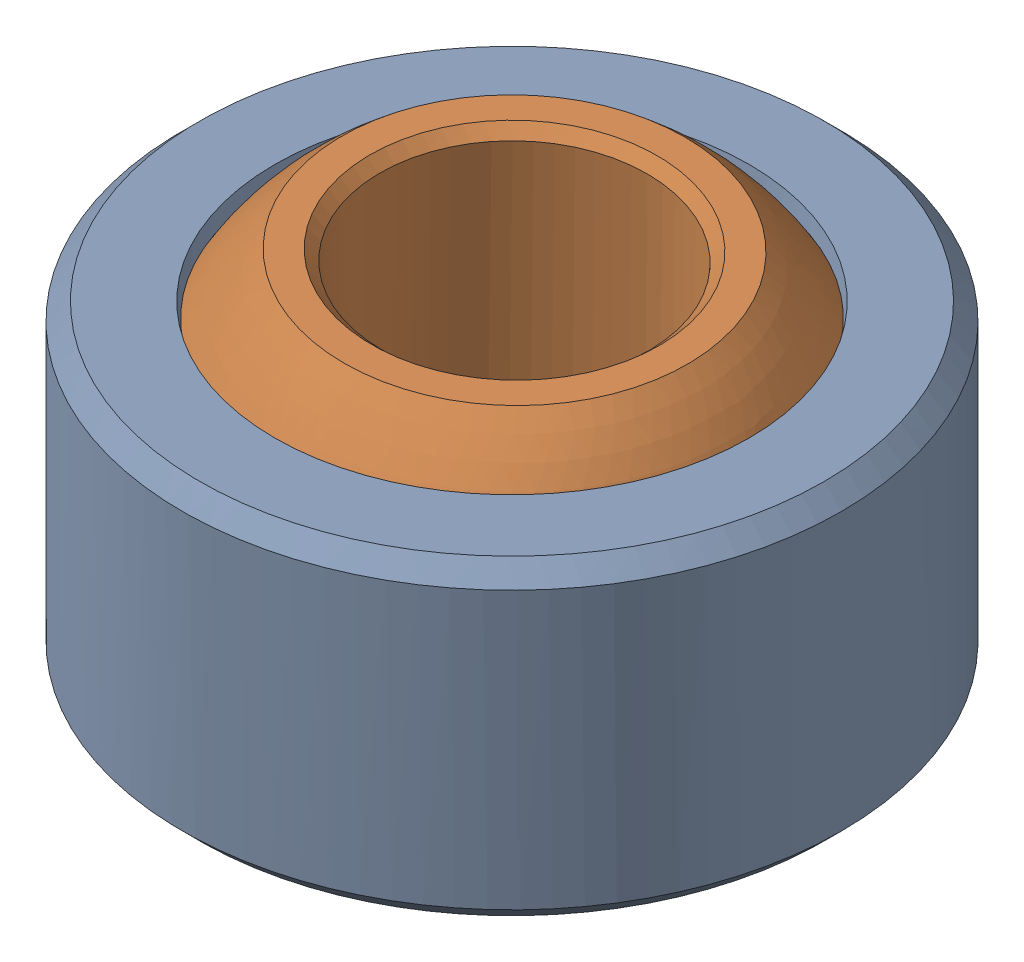
SolidWorks assembly M8Spherical, configuration Default. Lengths in mm.
Overall size (19.05 13.13 19.05).
2 component instances, 2 part files, 1 mates.
Components (placement in the parent):
- SPHolder-1: SPHolder [Default] at origin size (19.05 9 19.05)
- SPBall-1: SPBall [Default] x (0.99509 -0.039234 -0.090871) z (0.08959 -0.033259 0.995423) size (15.8 12 15.8)
Mates (geometry in assembly coordinates):
- Concentric1: concentric: sphere of SPHolder-1; sphere of SPBall-1
